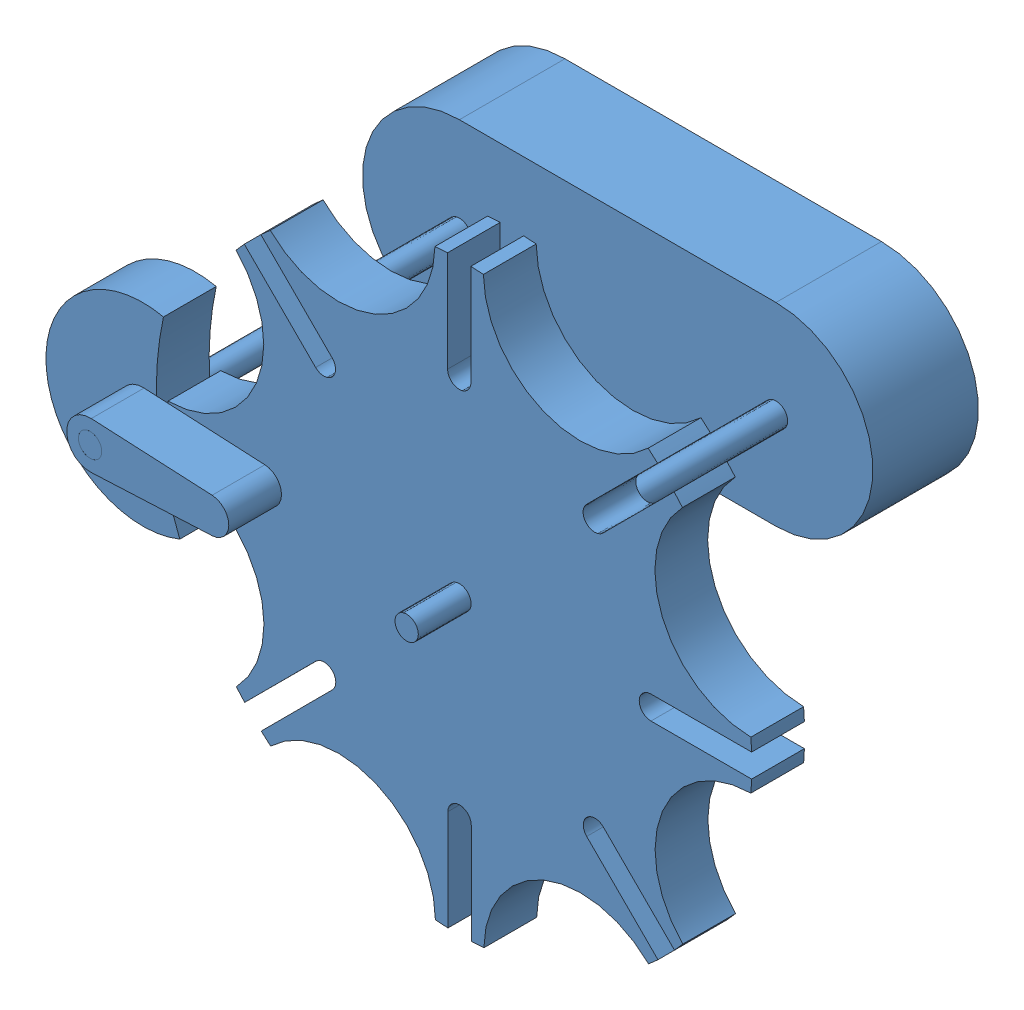
SolidWorks assembly Ensamble_Rueda_Ginebra_2, configuration Default. Lengths in mm.
Overall size (45.9 41.4 27).
3 component instances, 1 part files, 5 mates.
Components (placement in the parent):
- Rueda_Ginebra_5-3: Rueda_Ginebra_5 [Soporte] at (33.8881 0.3396 25.4558) size (29.02 11.02 27)
- Rueda_Ginebra_5-4: Rueda_Ginebra_5 [Disco_bloqueador] at (22.7538 -16.2996 25.4558) x (0.381426 -0.924399 0) z (0 0 1) size (11.02 12.87 6)
- Rueda_Ginebra_5-5: Rueda_Ginebra_5 [Default] at (33.8881 0.3396 25.4558) x (0.923557 0.383462 0) z (0 0 1) size (31.68 31.68 3)
Mates (geometry in assembly coordinates):
- Coincidente1: coincident aligned: plane of Rueda_Ginebra_5-3 through (15.8881 0.3396 28.4558) normal (0 0 1); plane of Rueda_Ginebra_5-4 through (15.8881 0.3396 28.4558) normal (0 0 1)
- Concéntrica1: concentric aligned: circle of Rueda_Ginebra_5-3; circle of Rueda_Ginebra_5-4
- Coincidente3: coincident anti-aligned: plane of Rueda_Ginebra_5-4 through (15.8881 0.3396 25.4558) normal (0 0 -1); plane of Rueda_Ginebra_5-5 through (33.8881 0.3396 25.4558) normal (0 0 1)
- Concéntrica2: concentric aligned: circle of Rueda_Ginebra_5-3; circle of Rueda_Ginebra_5-5
- Tangente3: tangent anti-aligned: cylinder of Rueda_Ginebra_5-4 through (22.7764 0.3302 22.4558) axis (0 0 1) radius 0.6652; plane of Rueda_Ginebra_5-5 through (33.8887 -0.3256 22.4558) normal (-0.000843 1 0)
